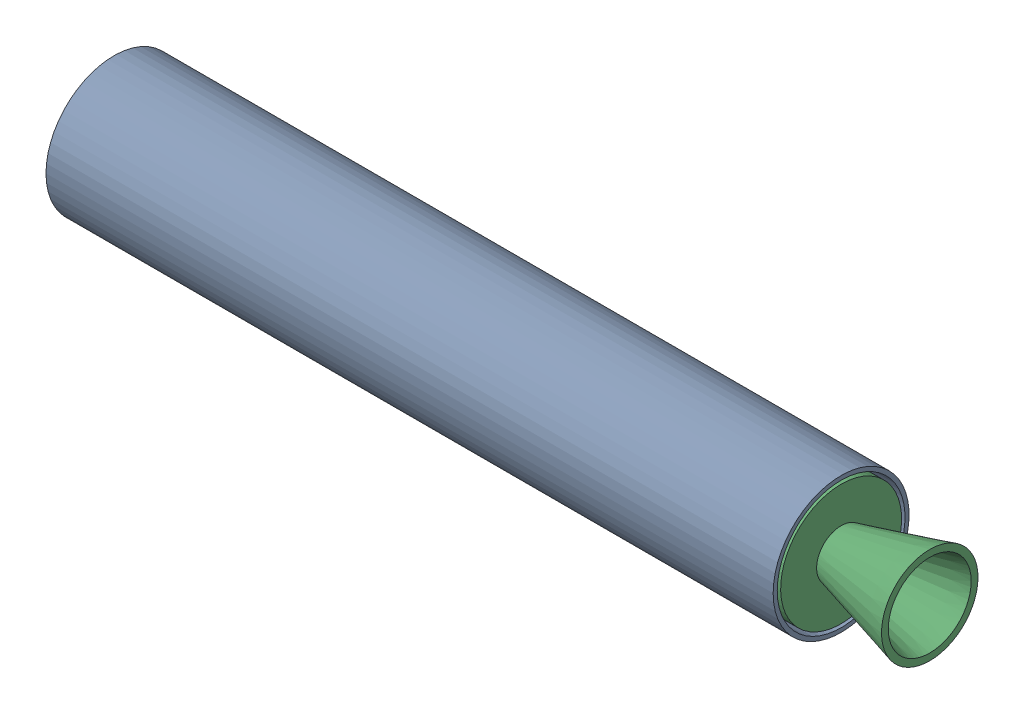
SolidWorks assembly 3_grain_Motor, configuration Default. Lengths in mm.
Overall size (600.2 100 100).
3 component instances, 3 part files, 4 mates.
Components (placement in the parent):
- 3_grain_Casing-1: 3_grain_Casing [Default] at (256.627 28.5581 -13.6644) x (0 1 0) z (0 0 1) size (100 535 100)
- Bulkhead-1: Bulkhead [Default] at (-278.373 28.5581 -13.6644) size (50 89 89)
- Nozzle2-1: Nozzle2 [Default] at (333.027 28.5581 -13.6644) size (115.2 88.99 88.99)
Mates (geometry in assembly coordinates):
- Concentric1: concentric anti-aligned: cylinder of 3_grain_Casing-1 through (-278.373 28.5581 -13.6644) axis (1 0 0) radius 47; cylinder of Bulkhead-1 through (-278.373 28.5581 -13.6644) axis (-1 0 0) radius 44.5
- Coincident1: coincident aligned: plane of 3_grain_Casing-1 through (-278.373 28.5581 -13.6644) normal (-1 0 0); plane of Bulkhead-1 through (-278.373 28.5581 -13.6644) normal (-1 0 0)
- Concentric2: concentric aligned: cylinder of 3_grain_Casing-1 through (-278.373 28.5581 -13.6644) axis (1 0 0) radius 47; cylinder of Nozzle2-1 through (333.027 28.5581 -13.6644) axis (1 0 0) radius 44.4963
- Coincident2: coincident aligned: plane of 3_grain_Casing-1 through (256.627 28.5581 -13.6644) normal (1 0 0); plane of Nozzle2-1 through (256.627 73.0544 -13.6644) normal (1 0 0)
